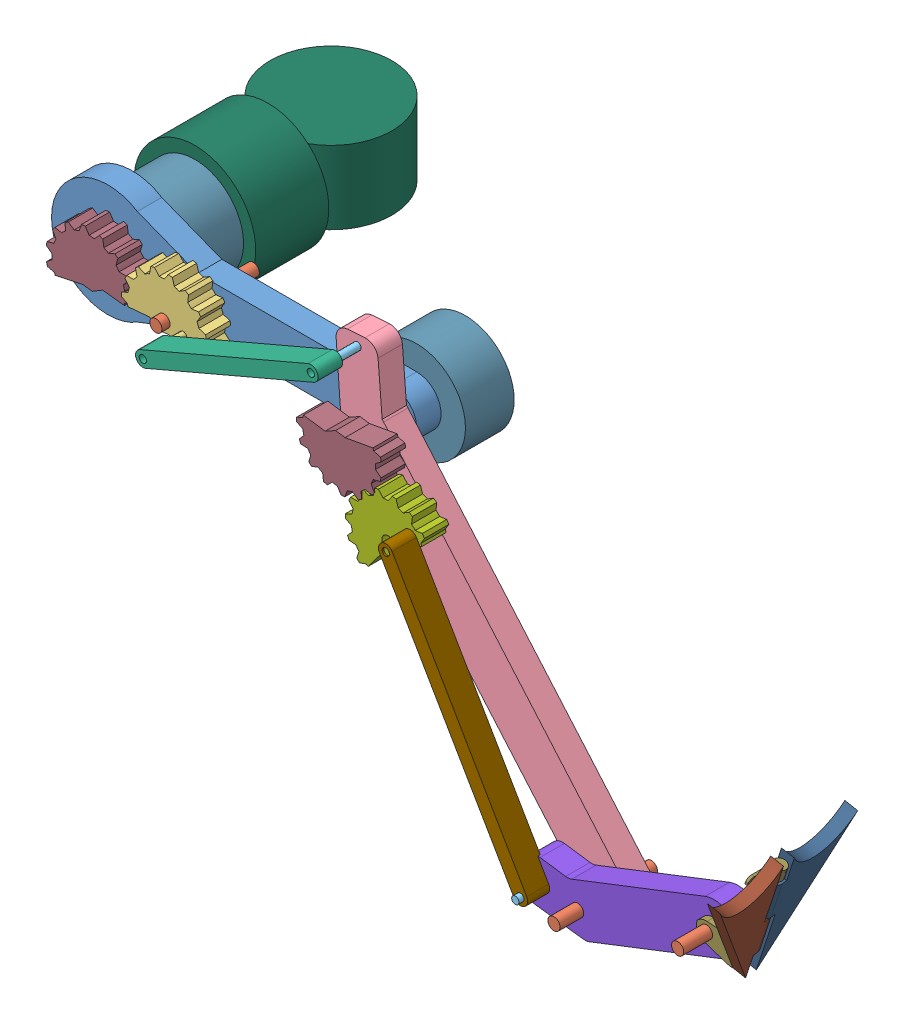
SolidWorks assembly Assemblage_leg, configuration Défaut. Lengths in mm.
Overall size (332.51 170.23 168.7).
22 component instances, 15 part files, 22 mates.
Components (placement in the parent):
- femur-1: femur [Défaut] at (-36.3804 -7.677 100) size (149.91 46.21 10)
- grand axe-1: grand axe [Défaut] at (-36.3804 2.323 87.1079) x (-0.546581 0.837406 0) z (0 0 1) size (5 5 40)
- PIGNON1-2: PIGNON1 [Défaut] at (-36.3804 2.323 113.7636) x (0.842709 -0.538369 0) z (0 0 1) size (34.33 27.43 20)
- tibia-1: tibia [Défaut] at (36.0482 -4.2095 111.1694) x (0.653255 -0.757138 0) z (0 0 1) size (192.09 33.32 10)
- petit axe-3: petit axe [Défaut] at (40.4681 30.5227 117.4187) x (-0.658639 0.752459 0) z (0 0 1) size (3 3 20)
- segment_L3-1: segment_L3 [Défaut] at (-27.3067 -1.7352 130.3308) x (0.919398 0.393329 0) z (0 0 1) size (81 6 10)
- PIGNON2-1: PIGNON2 [Défaut] at (63.3343 -22.7445 121.5567) x (0.96371 0.266952 0) z (0 0 1) size (34.33 27.43 20)
- grand axe-4: grand axe [Défaut] at (142.9144 -112.7619 102.9566) x (0.597942 -0.80154 0) z (0 0 1) size (5 5 40)
- tarto-1: tarto [Défaut] at (146.5368 -122.0828 123.2421) x (0.932083 0.362245 0) z (0 0 1) size (91.56 26.49 10)
- petit axe-4: petit axe [Défaut] at (128.4362 -110.9563 124.3445) x (1 -0.000714 0) z (0 0 1) size (3 3 20)
- segment_L3 - Copie-1: segment_L3 - Copie [Défaut] at (70.5652 -17.3617 132.251) x (0.502521 -0.864565 0) z (0 0 1) size (116 6 10)
- grand axe-5: grand axe [Défaut] at (198.8393 -91.0272 108.1237) x (0.981676 0.190558 0) z (0 0 1) size (5 5 40)
- palme_last_v-2: palme_last_v [Défaut] at (270.1498 -87.907 119.3623) x (-0.100123 0.032843 -0.994433) z (-0.944895 0.309952 0.105372) size (63.15 52.21 24.3)
  - part1_palme-1: part1_palme [Défaut] at (-7.6046 -22.9375 50) size (34.09 50 5)
  - part2_palme-1: part2_palme [Défaut] at (-12.5766 -22.9375 54.9823) x (-1 0 0) z (0 0 -1) size (34.09 50 5)
  - arret_rotation-1: arret_rotation [Défaut] at (-10.0906 -19.7229 52.4912) x (0.105372 0 0.994433) z (0 1 0) size (22.5 18.23 49)
- PIGNON_moteur-2: PIGNON_moteur [Défaut] at (-67.4715 2.323 123.6642) x (-0.858016 -0.513623 0) z (0 0 -1) size (34.33 27.43 20)
- PIGNON_moteur-3: PIGNON_moteur [Défaut] at (43.6196 2.323 131.8538) x (0.874029 0.485874 0) z (0 0 -1) size (34.33 27.43 20)
- moteur-1: moteur [Défaut] at (-67.4715 2.323 80) size (40 40 30)
- moteur-2: moteur [Défaut] at (43.6196 2.323 80) size (40 40 30)
- moteur_hanche-1: moteur_hanche [Défaut] at (-67.4715 2.323 50) x (0.975295 -0.220906 0) z (0 0 1) size (50 50 30)
- moteur_hanche-2: moteur_hanche [Défaut] at (-66.5739 17.9057 25) x (0.999975 0 0.007054) z (0 -1 0) size (50 50 30)
Mates (geometry in assembly coordinates):
- Coaxiale1: concentric aligned: cylinder of femur-1 through (-36.3804 2.323 110) axis (0 0 -1) radius 2.5; cylinder of grand axe-1 through (-36.3804 2.323 127.1079) axis (0 0 -1) radius 2.5
- Coaxiale6: concentric anti-aligned: cylinder of grand axe-1 through (-36.3804 2.323 127.1079) axis (0 0 -1) radius 2.5; cylinder of PIGNON1-2 through (-36.3804 2.323 113.7636) axis (0 0 1) radius 2.5
- Coaxiale11: concentric aligned: cylinder of PIGNON1-2 through (-28.4867 1.023 133.7636) axis (0 0 -1) radius 1.5; cylinder of segment_L3-1 through (-28.4867 1.023 140.3308) axis (0 0 -1) radius 1.5
- Coaxiale12: concentric aligned: cylinder of petit axe-3 through (40.4681 30.5227 137.4187) axis (0 0 -1) radius 1.5; cylinder of segment_L3-1 through (40.4681 30.5227 140.3308) axis (0 0 -1) radius 1.5
- Coaxiale15: concentric aligned: cylinder of grand axe-4 through (142.9144 -112.7619 142.9566) axis (0 0 -1) radius 2.5; cylinder of tarto-1 through (142.9144 -112.7619 133.2421) axis (0 0 -1) radius 2.5
- Coaxiale16: concentric aligned: cylinder of tarto-1 through (128.4362 -110.9563 133.2421) axis (0 0 -1) radius 1.5; cylinder of petit axe-4 through (128.4362 -110.9563 144.3445) axis (0 0 -1) radius 1.5
- Coaxiale17: concentric anti-aligned: cylinder of petit axe-4 through (128.4362 -110.9563 144.3445) axis (0 0 -1) radius 1.5; circle of segment_L3 - Copie-1
- Coaxiale18: concentric aligned: cylinder of PIGNON2-1 through (73.1589 -15.8542 141.5567) axis (0 0 -1) radius 1.5; cylinder of segment_L3 - Copie-1 through (73.1589 -15.8542 142.251) axis (0 0 -1) radius 1.5
- Coaxiale20: concentric aligned: cylinder of tarto-1 through (198.8393 -91.0272 133.2421) axis (0 0 -1) radius 2.5; cylinder of grand axe-5 through (198.8393 -91.0272 148.1237) axis (0 0 -1) radius 2.5
- Coaxiale21: concentric aligned: cylinder of grand axe-5 through (198.8393 -91.0272 148.1237) axis (0 0 -1) radius 2.5; cylinder of palme_last_v-2/arret_rotation-1 through (198.8393 -91.0272 143.5852) axis (0 0 -1) radius 2.5
- Coaxiale24: concentric anti-aligned: cylinder of femur-1 through (-67.4715 2.323 110) axis (0 0 -1) radius 2.5; cylinder of PIGNON_moteur-2 through (-67.4715 2.323 103.6642) axis (0 0 1) radius 2.5
- Coaxiale26: concentric aligned: cylinder of tibia-1 through (142.9144 -112.7619 121.1694) axis (0 0 -1) radius 2.5; cylinder of grand axe-4 through (142.9144 -112.7619 142.9566) axis (0 0 -1) radius 2.5
- Coaxiale27: concentric aligned: cylinder of tibia-1 through (40.4681 30.5227 121.1694) axis (0 0 -1) radius 1.5; cylinder of petit axe-3 through (40.4681 30.5227 137.4187) axis (0 0 -1) radius 1.5
- Coaxiale28: concentric anti-aligned: cylinder of tibia-1 through (43.6196 2.323 121.1694) axis (0 0 -1) radius 2.5; cylinder of PIGNON_moteur-3 through (43.6196 2.323 111.8538) axis (0 0 1) radius 2.5
- Coaxiale29: concentric aligned: cylinder of femur-1 through (-67.4715 2.323 110) axis (0 0 -1) radius 2.5; cylinder of moteur-1 through (-67.4715 2.323 110) axis (0 0 -1) radius 2.5
- Coïncidente1: coincident anti-aligned: plane of femur-1 through (-73.1882 2.323 100) normal (0 0 -1); plane of moteur-1 through (-67.4715 2.323 100) normal (0 0 1)
- Coaxiale30: concentric anti-aligned: cylinder of femur-1 through (43.6196 2.323 110) axis (0 0 -1) radius 2.5; cylinder of PIGNON_moteur-3 through (43.6196 2.323 111.8538) axis (0 0 1) radius 2.5
- Coaxiale31: concentric aligned: cylinder of femur-1 through (43.6196 2.323 110) axis (0 0 -1) radius 2.5; cylinder of moteur-2 through (43.6196 2.323 110) axis (0 0 -1) radius 2.5
- Coïncidente2: coincident anti-aligned: plane of femur-1 through (-73.1882 2.323 100) normal (0 0 -1); plane of moteur-2 through (43.6196 2.323 100) normal (0 0 1)
- Coaxiale32: concentric aligned: cylinder of moteur-1 through (-67.4715 2.323 100) axis (0 0 -1) radius 20; cylinder of moteur_hanche-1 through (-67.4715 2.323 80) axis (0 0 -1) radius 25
- Coïncidente3: coincident anti-aligned: plane of moteur-1 through (-67.4715 2.323 80) normal (0 0 -1); plane of moteur_hanche-1 through (-67.4715 2.323 80) normal (0 0 1)
- Tangent1: tangent anti-aligned: plane of moteur_hanche-1 through (-67.4715 2.323 50) normal (0 0 -1); cylinder of moteur_hanche-2 through (-66.5739 -12.0943 25) axis (0 1 0) radius 25
